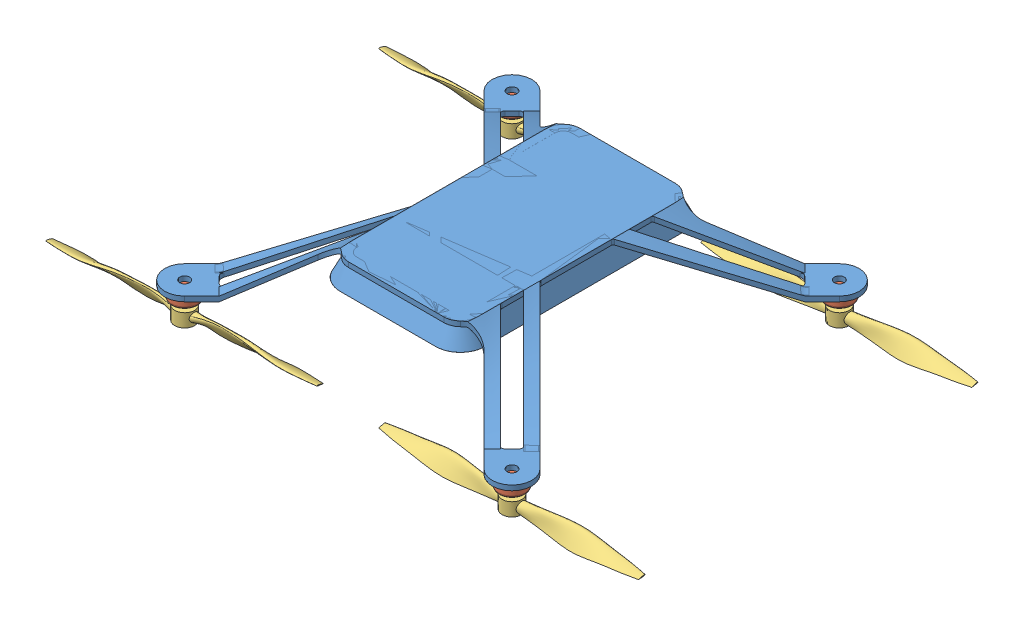
SolidWorks assembly Drone Assembly, configuration Default. Lengths in mm.
Overall size (356.35 58.23 221.99).
9 component instances, 3 part files, 6 mates.
Components (placement in the parent):
- Base-1: Base [Default] at (67.332 117.4016 165.2611) size (221.99 39.54 221.99)
- motor-1: motor [Default] at (-31.6629 85.8866 66.2661) x (0.95596 0 -0.293496) z (-0.293496 0 -0.95596) size (16 12 16)
- motor-2: motor [Default] at (166.327 85.8866 66.2661) x (0.293496 0 0.95596) z (0.95596 0 -0.293496) size (16 12 16)
- motor-3: motor [Default] at (166.327 85.8866 264.256) x (-0.95596 0 0.293496) z (0.293496 0 0.95596) size (16 12 16)
- motor-4: motor [Default] at (-31.6629 85.8866 264.256) x (-0.293496 0 -0.95596) z (-0.95596 0 0.293496) size (16 12 16)
- Propeller-1: Propeller [Default] at (170.3269 101.9016 264.2782) x (0.005544 0 -0.999985) z (0.999985 0 0.005544) size (12 10.47 158.02)
- Propeller-2: Propeller [Default] at (-35.6629 101.9016 66.244) x (-0.005544 0 0.999985) z (-0.999985 0 -0.005544) size (12 10.47 158.02)
- Propeller-5: Propeller [Default] at (170.324 101.9016 66.1134) x (-0.038174 0 -0.999271) z (0.999271 0 -0.038174) size (12 10.47 158.02)
- Propeller-8: Propeller [Default] at (-35.66 101.9016 264.4087) x (0.038174 0 0.999271) z (-0.999271 0 0.038174) size (12 10.47 158.02)
Mates (geometry in assembly coordinates):
- Coincident2: coincident anti-aligned: plane of Base-1 through (-31.6629 115.9016 66.2661) normal (0 -1 0); plane of motor-1 through (-31.6629 115.9016 66.2661) normal (0 1 0)
- Concentric1: concentric aligned: cylinder of Base-1 through (-31.6629 118.9016 66.2661) axis (0 -1 0) radius 3; cylinder of motor-1 through (-31.6629 39.8104 66.2661) axis (0 -1 0) radius 4.5
- Coincident4: coincident anti-aligned: circle of motor-3; plane of Propeller-1 through (166.327 105.9016 264.256) normal (0 1 0)
- Concentric3: concentric aligned: cylinder of motor-3 through (166.327 39.8104 264.256) axis (0 -1 0) radius 1.5; cylinder of Propeller-1 through (166.327 105.9016 264.256) axis (0 -1 0) radius 1.5
- Coincident5: coincident anti-aligned: circle of motor-2; plane of Propeller-5 through (166.327 105.9016 66.2661) normal (0 1 0)
- Concentric4: concentric aligned: cylinder of motor-2 through (166.327 39.8104 66.2661) axis (0 -1 0) radius 1.5; cylinder of Propeller-5 through (166.327 105.9016 66.2661) axis (0 -1 0) radius 1.5
